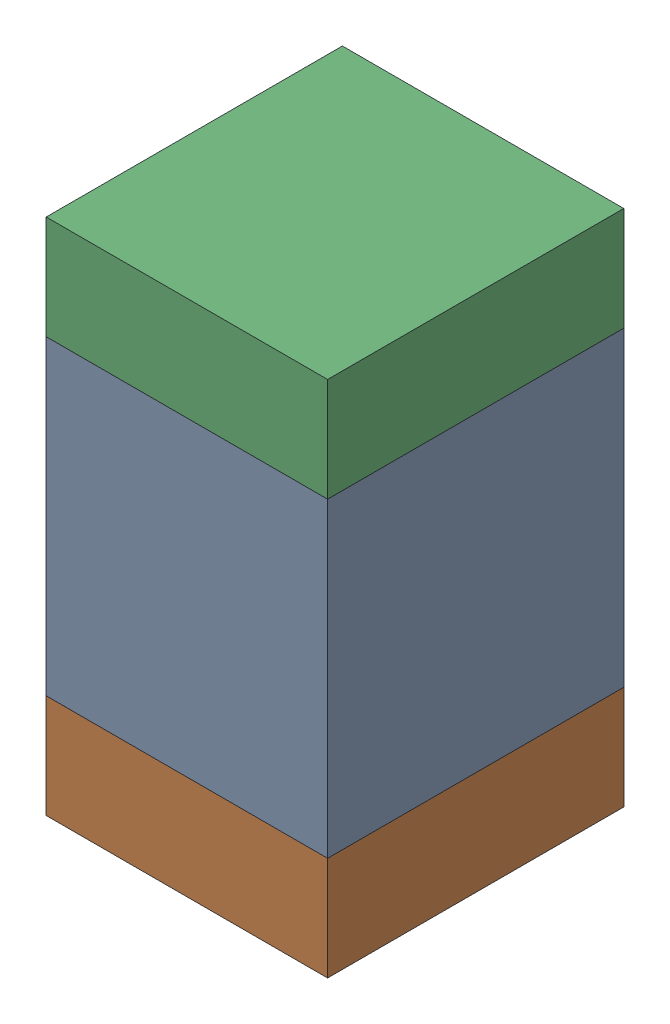
SolidWorks assembly C402PCB, configuration Default. Lengths in mm.
Overall size (0.95 1.75 1).
6 component instances, 2 part files, 0 mates.
Components (placement in the parent):
- 761616384-1: 761616384 [Default] at (82.6 81.9 0) size (0.95 1.05 1)
  - Extruded_5-1: Extruded_5 [Default] at origin size (0.95 1.05 1)
- 761616520-1: 761616520 [Default] at (82.6 81.2 0) size (0.95 0.35 1)
  - Extruded_6-1: Extruded_6 [Default] at origin size (0.95 0.35 1)
- 761616520-2: 761616520 [Default] at (82.6 82.6 0) size (0.95 0.35 1)
  - Extruded_6-1: Extruded_6 [Default] at origin size (0.95 0.35 1)
